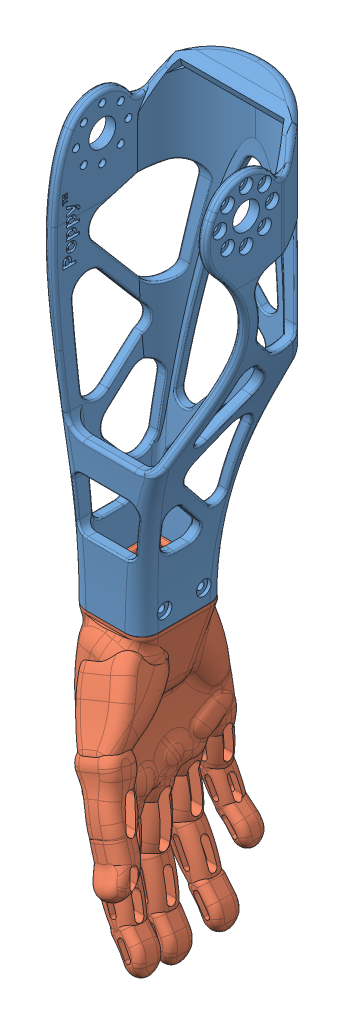
SolidWorks assembly arm_r3, configuration Default. Lengths in mm.
Overall size (55.2 228.71 65.03).
2 component instances, 2 part files, 3 mates.
Components (placement in the parent):
- arm_forearm_right-1: arm_forearm_right [MX-28-right] at (13.5631 144.0672 118.4049) size (55.2 137.66 53.14)
- arm_hand_right-1: arm_hand_right [left_fake_human_like_hand] at (3.2131 24.0672 114.4049) x (0 0 -1) z (0 -1 0) size (59.65 36.84 100.68)
Mates (geometry in assembly coordinates):
- Concentric1: concentric anti-aligned: cylinder of arm_forearm_right-1 through (18.0631 29.0672 120.4049) axis (1 0 0) radius 1.1; cylinder of arm_hand_right-1 through (14.2131 29.0672 120.4049) axis (-1 0 0) radius 1.1
- Concentric2: concentric anti-aligned: cylinder of arm_forearm_right-1 through (18.0631 29.0672 108.4049) axis (1 0 0) radius 1.1; cylinder of arm_hand_right-1 through (14.2131 29.0672 108.4049) axis (-1 0 0) radius 1.1
- Tangent1: tangent: face of arm_forearm_right-1; plane of arm_hand_right-1 through (11.0631 33.0672 122.4049) normal (1 0 0)
